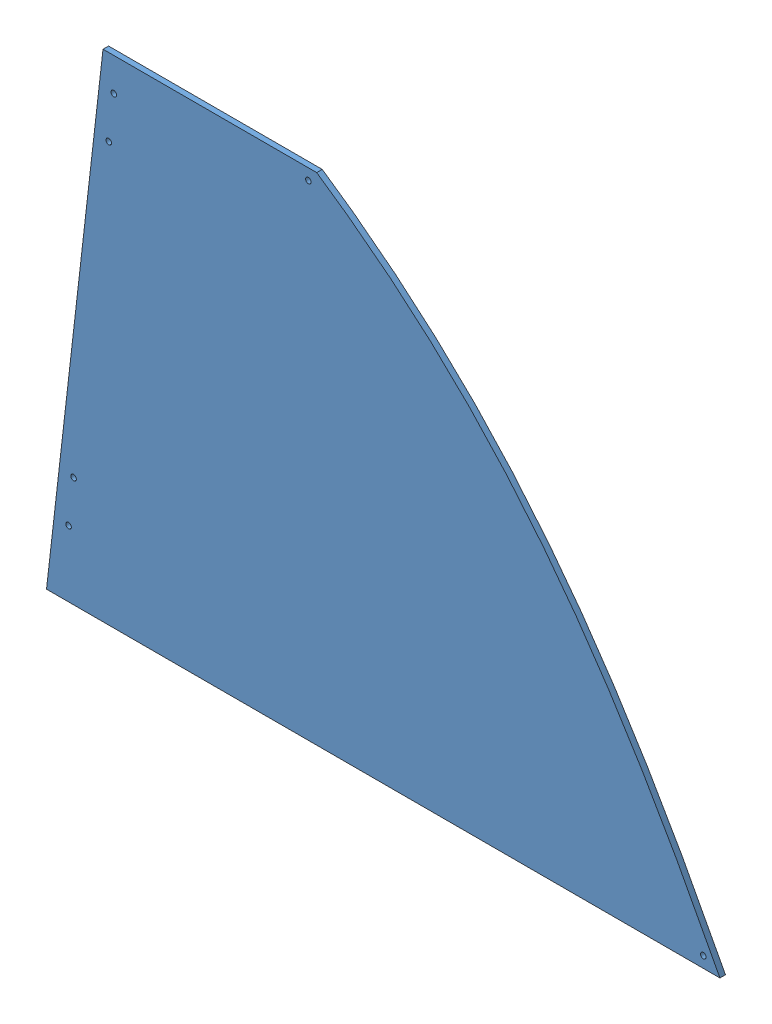
SolidWorks assembly GE-19080-Right-Blue, configuration Default. Lengths in mm.
Overall size (771.1 567.83 44.58).
2 component instances, 2 part files, 3 mates.
Components (placement in the parent):
- GE-19080-1: GE-19080 [GE-19080] at origin size (771.1 567.83 6.35)
- GE-19080-Right-Blue-Vinyl-1: GE-19080-Right-Blue-Vinyl [Notched] at (0 0 6.35) size (771.1 567.83 0.13)
Mates (geometry in assembly coordinates):
- Coincident1: coincident: plane of assembly; plane of assembly; plane of GE-19080-1 through (546.1766 314.686 6.35) normal (0 0 1); plane of GE-19080-Right-Blue-Vinyl-1 through (546.1766 314.686 6.35) normal (0 0 -1)
- Coincident2: coincident: plane of assembly; plane of assembly; plane of GE-19080-1 through (32.7402 567.8263 582.3432) normal (-0.993572 0.113203 0); plane of GE-19080-Right-Blue-Vinyl-1 through (32.7402 567.8263 582.4702) normal (-0.993572 0.113203 0)
- Coincident3: coincident: plane of assembly; plane of assembly; plane of GE-19080-1 through (0 0 6.35) normal (0 -1 0); plane of GE-19080-Right-Blue-Vinyl-1 through (0 0 6.477) normal (0 -1 0)
